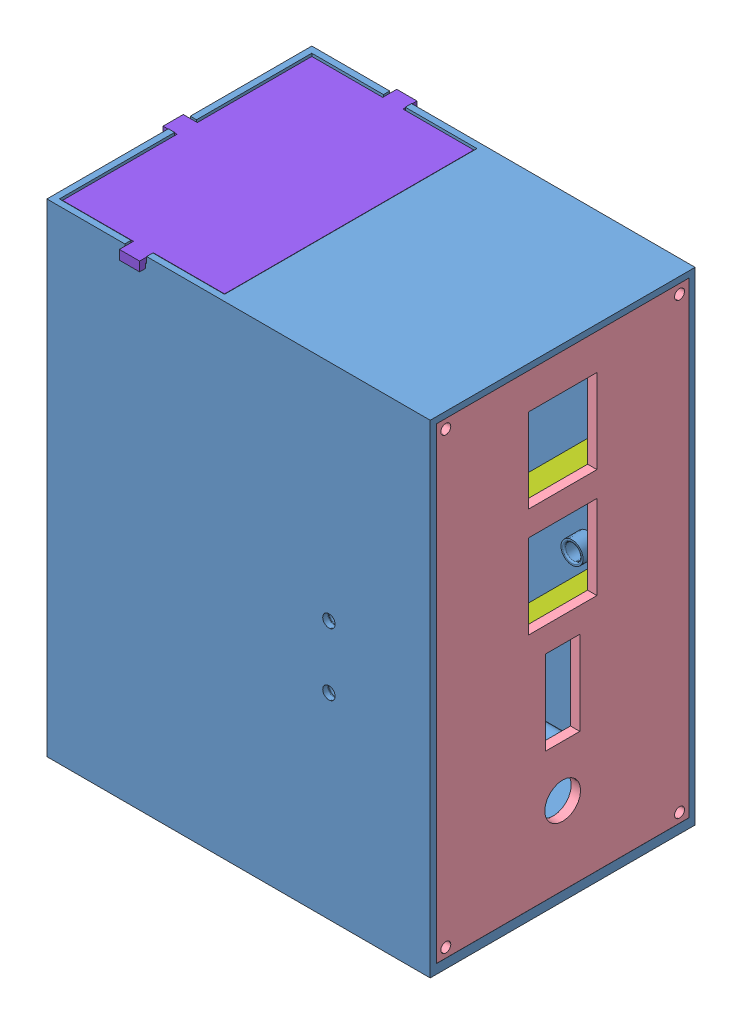
SolidWorks assembly Assembly of Full Enclosure, configuration Default. Lengths in mm.
Overall size (125.04 155 89).
9 component instances, 8 part files, 0 mates.
Components (placement in the parent):
- Main Body-1: Main Body [Default] at (54.0762 -5.6924 166.2098) size (123 155 85)
- Servo Arm-1: Servo Arm [Default] at (86.3977 30.4823 123.726) size (96.42 3 47.43)
- Servo Bracket-1: Servo Bracket [Default] at (74.019 3.0835 114.6789) x (0 0 1) z (-1 0 0) size (18 18 23)
- Side Panel-1: Side Panel [Default] at (119.0586 -2.6789 164.1895) x (0 0 -1) z (0 -1 0) size (81 3 150)
- Ultrasonic Bracket-1: Ultrasonic Bracket [Default] at (43.2937 136.1853 123.6731) x (0 0 -1) z (1 0 0) size (47 35 29)
- Ultrasonic Hood-1: Ultrasonic Hood [Default] at (54.076 126.3342 99.7104) x (0 0 1) z (0 -1 0) size (50 29 21)
- L Beam-1: L Beam [Default] at (119.0326 69.7053 83.198) x (0 0 1) z (1 0 0) size (81 12 10)
- L Beam-2: L Beam [Default] at (119.3897 103.3374 164.2073) x (0 0 -1) z (1 0 0) size (81 12 10)
- Top Lid Modified-1: Top Lid Modified [Default] at (54.0342 147.3625 83.1587) x (-1 0 0) z (0 0 -1) size (56.5 3 89)
